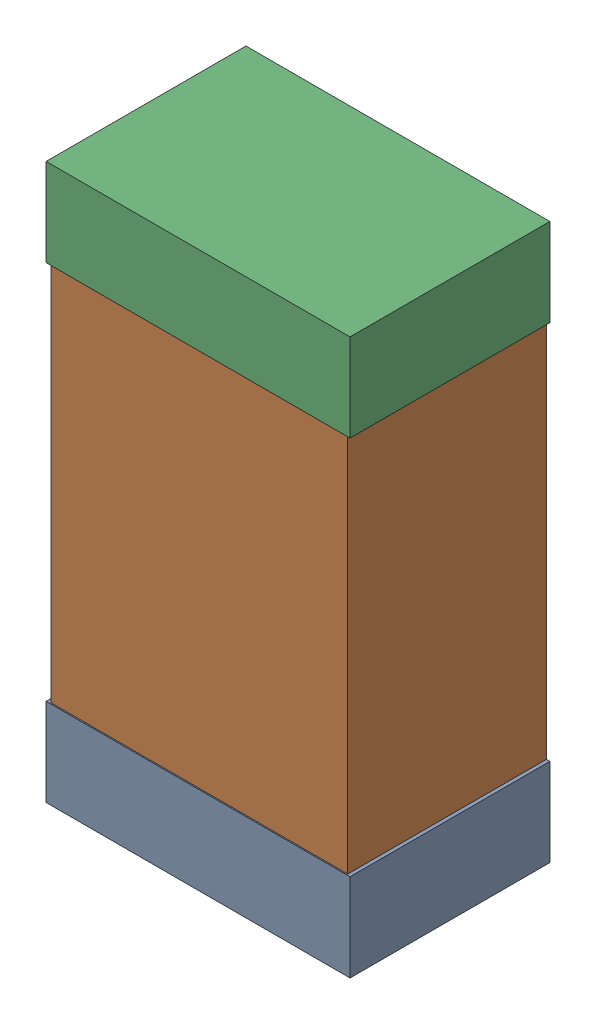
SolidWorks assembly 953kKanaloa_v2.0.0_Power, configuration Default. Lengths in mm.
Overall size (1.3 2.38 0.85).
6 component instances, 2 part files, 0 mates.
Components (placement in the parent):
- 330415056-1: 330415056 [Default] at (148.4768 96.0454 0) size (1.3 0.38 0.85)
  - Extruded_2-1: Extruded_2 [Default] at origin size (1.3 0.38 0.85)
- 334787376-1: 334787376 [Default] at (148.4768 97.0454 0) size (1.27 2.2 0.85)
  - Extruded_16-1: Extruded_16 [Default] at origin size (1.27 2.2 0.85)
- 330415056-2: 330415056 [Default] at (148.4768 98.0454 0) size (1.3 0.38 0.85)
  - Extruded_2-1: Extruded_2 [Default] at origin size (1.3 0.38 0.85)
